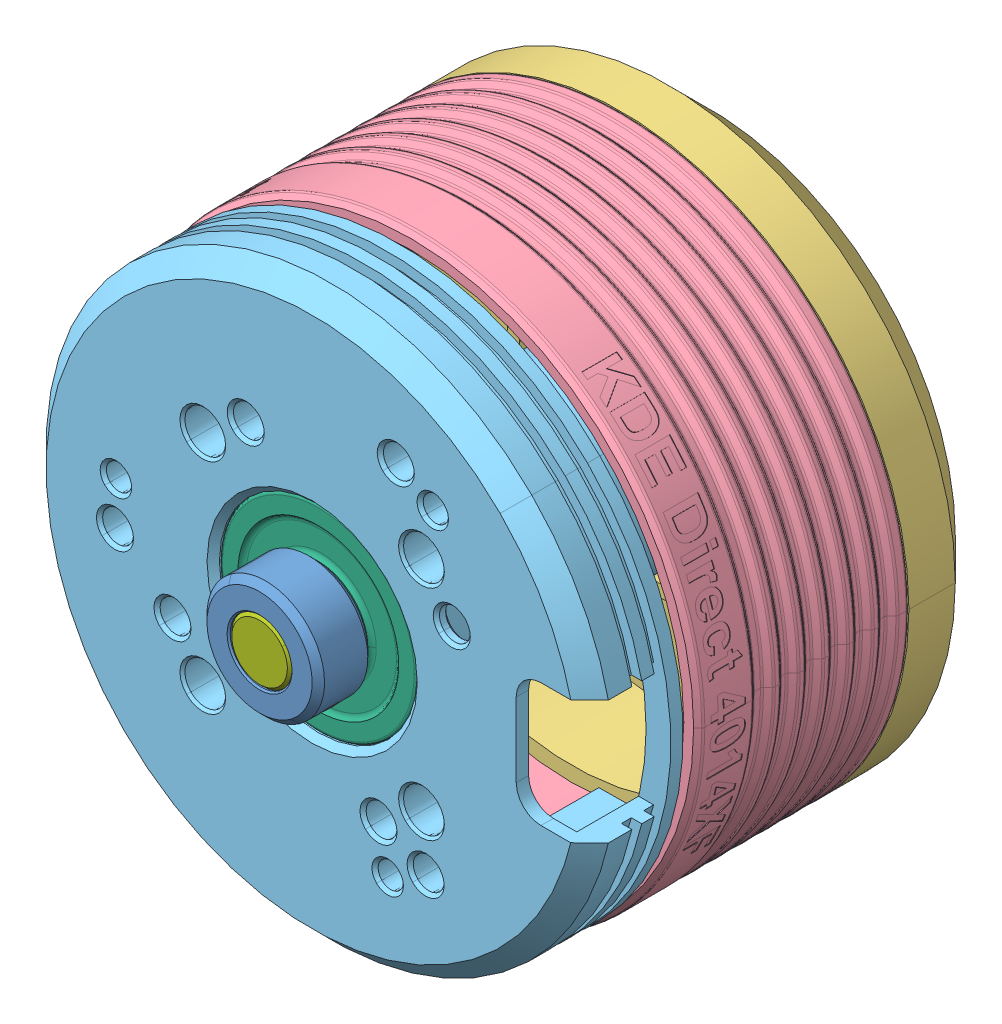
SolidWorks assembly KDE4014XF-380KV, configuration Default. Lengths in mm.
Overall size (65.05 65.05 41.75).
10 component instances, 7 part files, 0 mates.
Components (placement in the parent):
- KDE4014XF-380KV.STEP-1: KDE4014XF-380KV.STEP [Default] at origin size (65.05 65.05 41.75)
  - KDE-D5-SECURITY-RING-ASSEMBLY.STEP-1: KDE-D5-SECURITY-RING-ASSEMBLY.STEP [Default] at (0 0 23) x (-0.587785 0.809017 0) z (0 0 1) size (9.5 9.5 4.75)
    - KDE-D5-SECURITY_RING.STEP-1: KDE-D5-SECURITY_RING.STEP [Default] at origin size (9.5 9.5 4.75)
    - M3 x 3MM SOCKET HEAD SET SCREW KNURLED CUP POINT.STEP-1: M3 x 3MM SOCKET HEAD SET SCREW KNURLED CUP POINT.STEP [Default] at (0 3.375 2) x (-1 0 0) z (0 1 0) size (3 3 3.01)
    - M3 x 3MM SOCKET HEAD SET SCREW KNURLED CUP POINT.STEP-2: M3 x 3MM SOCKET HEAD SET SCREW KNURLED CUP POINT.STEP [Default] at (-3.375 0 2) x (0 0 -1) z (-1 0 0) size (3 3 3.01)
  - DT3914-24P-FRONT-COVER-D5-V2.STEP-1: DT3914-24P-FRONT-COVER-D5-V2.STEP [Default] at origin size (46.5 46.5 11)
  - DT3914-HOUSING.STEP-1: DT3914-HOUSING.STEP [Default] at origin size (46.5 46.5 17)
  - DT3914-REAR-COVER.STEP-1: DT3914-REAR-COVER.STEP [Default] x (-0.707107 -0.707107 0) z (0 0 -1) size (46 46 25)
  - RADIAL BALL BEARING 625ZZ.STEP-1: RADIAL BALL BEARING 625ZZ.STEP [Default] at (0 0 20) size (16 16 5)
  - DT3914-SHAFT-D5-V2.STEP-1: DT3914-SHAFT-D5-V2.STEP [Default] at (0 0 -11.75) x (-0.809017 -0.587785 0) z (0 0 1) size (6 6 41.75)
